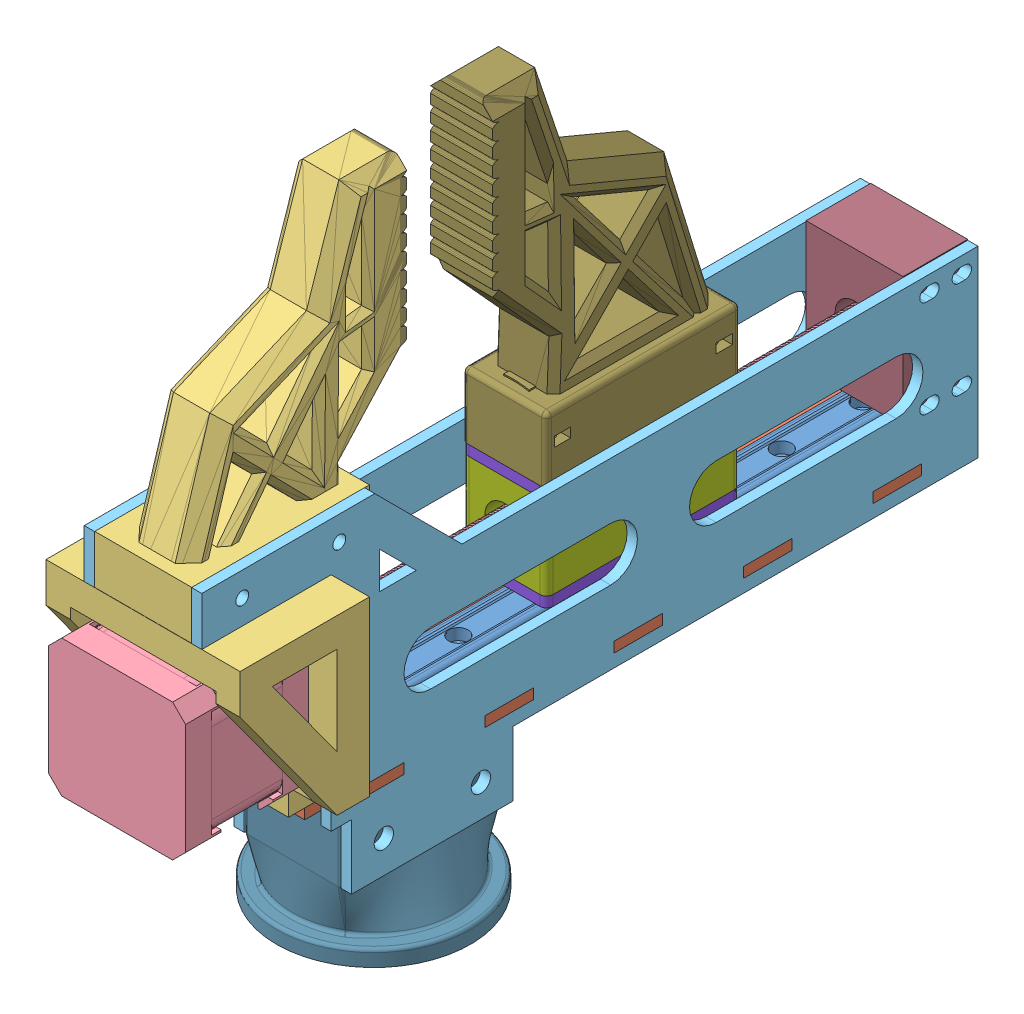
SolidWorks assembly CAD, configuration Default. Lengths in mm.
Overall size (60 201.12 248).
17 component instances, 14 part files, 31 mates.
Components (placement in the parent):
- Em4HMIiUfR_CADModel_0-1: Em4HMIiUfR_CADModel_0 [Default] at origin size (13.08 8.01 200)
- Part1-1: Part1 [Default] at (-24.2561 0 -84.2912) x (1 0 0) z (0 1 0) size (36.35 200 3.17)
- Part4-1: Part4 [Default] at (30 8.03 40) x (-1 0 0) z (0 0 -1) size (60 153.95 71.54)
- Stepper with LeadScrew-1: Stepper with LeadScrew [Default] at (0 29.78 18) x (1 0 0) z (0 1 0) size (42.3 239.5 42.3)
- Part2-1: Part2 [Default] at (18.175 145.03 -15) x (0 0 -1) z (1 0 0) size (240 103.7 3.17)
- 7917N13_HIGH-CYCLE LOW-PROFILE BALL BEARING CARRIAGE-1: 7917N13_HIGH-CYCLE LOW-PROFILE BALL BEARING CARRIAGE [7917N13] at (0.4 7.1 -102.0336) size (27 11 34.4)
- spring mech-1: spring mech [Default] at (6.5573 38.7283 -72.0092) x (0 0 1) z (0 -1 0) size (60 26 32.35)
  - Block1-1: Block1 [Default] at (-59.7244 -6.4427 -4.0467) size (60 26 26)
  - spring plate-1: spring plate [Default] at (-59.7244 -6.4427 -4.0467) x (-1 0 0) z (0 0 -1) size (60 26 3.17)
  - spring plate-2: spring plate [Default] at (0.2756 -6.4427 21.9533) size (60 26 3.17)
  - leadnut-1: leadnut [Default] at (-36.9744 6.5573 8.9533) x (-1 0 0) z (0 -1 0) size (10 24 10.5)
  - 9434K135_MUSIC-WIRE STEEL COMPRESSION SPRINGS-1: 9434K135_MUSIC-WIRE STEEL COMPRESSION SPRINGS [9434K135] at (-41.4744 6.4644 9.0297) x (0 -1 0) z (0 0 1) size (15.72 32.66 15.84)
  - guide block-1: guide block [Default] at (-41.4744 -1.4427 21.9533) x (0 1 0) z (-1 0 0) size (16 26 7)
- pincher-1: pincher [Default] at (-85.0656 -1.6348 38.7958) x (1 0 0) z (0 1 0) size (26 73.24 107.42)
- Part2-2: Part2 [Default] at (-15 145.03 -15) x (0 0 -1) z (1 0 0) size (240 103.7 3.17)
- Part3-1: Part3 [Default] at (-15 9.78 -200) size (30 40 20)
- Circular Wrist Adapter Mount-1: Circular Wrist Adapter Mount [Default] at (0 -42.175 -31.2815) x (0 0 1) z (0 1 0) size (60 60 40)
Mates (geometry in assembly coordinates):
- Coincident1: coincident anti-aligned: plane of Em4HMIiUfR_CADModel_0-1 through (-5.8438 0 -200) normal (0 -1 0); plane of Part1-1 through (-24.2561 0 -84.2912) normal (0 1 0)
- Coincident2: coincident aligned: circle of Em4HMIiUfR_CADModel_0-1; cylinder of Part1-1 through (0 -3.175 -32.5) axis (0 1 0) radius 1.75
- Concentric2: concentric aligned: circle of Em4HMIiUfR_CADModel_0-1; circle of Part1-1
- Concentric3: concentric aligned: circle of Part4-1; circle of Stepper with LeadScrew-1
- Coincident3: coincident anti-aligned: plane of Part4-1 through (30 8.03 10) normal (0 0 1); plane of Stepper with LeadScrew-1 through (0 29.78 10) normal (0 0 -1)
- Parallel1: parallel aligned: plane of Part4-1 through (-30 48.03 0) normal (-1 0 0); plane of Stepper with LeadScrew-1 through (-21.1 44.68 40) normal (-1 0 0)
- Distance1: distance = 5 mm anti-aligned: plane of Part1-1 through (-18.175 -3.175 5) normal (0 0 1); plane of Part4-1 through (30 8.03 0) normal (0 0 -1)
- Parallel2: parallel anti-aligned: plane of Part1-1 through (-24.2561 -3.175 -84.2912) normal (0 -1 0); plane of Part4-1 through (-15 76.53 39.9268) normal (0 1 0)
- Coincident7: coincident aligned: plane of Part1-1 through (-15 -10 17.5) normal (-1 0 0); plane of Part4-1 through (-15 8.03 40) normal (-1 0 0)
- Coincident8: coincident anti-aligned: plane of Part1-1 through (18.175 -10 -7.5) normal (0 0 1); plane of Part2-1 through (15 -3.175 -7.5) normal (0 0 -1)
- Coincident9: coincident anti-aligned: plane of Part1-1 through (15 -10 17.5) normal (1 0 0); plane of Part2-1 through (15 145.03 -15) normal (-1 0 0)
- Coincident10: coincident anti-aligned: plane of Part1-1 through (-24.2561 0 -84.2912) normal (0 1 0); plane of Part2-1 through (15 0 -102.5) normal (0 -1 0)
- Distance2: distance = 13 mm aligned: plane of 7917N13_HIGH-CYCLE LOW-PROFILE BALL BEARING CARRIAGE-1 through (-12 13 -112.3336) normal (0 1 0); plane of Part1-1 through (-24.2561 0 -84.2912) normal (0 1 0)
- Coincident14: coincident anti-aligned: plane of 7917N13_HIGH-CYCLE LOW-PROFILE BALL BEARING CARRIAGE-1 through (-12.69 13.6 -84.8336) normal (0 1 0); plane of spring mech-1/spring plate-2 through (13 13.6 -71.7336) normal (0 -1 0)
- Coincident15: coincident aligned: plane of 7917N13_HIGH-CYCLE LOW-PROFILE BALL BEARING CARRIAGE-1 through (-13 12 -91.7336) normal (-1 0 0); plane of spring mech-1/Block1-1 through (-13 16.775 -129.7336) normal (-1 0 0)
- Distance3: distance = 12.5 mm aligned: plane of 7917N13_HIGH-CYCLE LOW-PROFILE BALL BEARING CARRIAGE-1 through (-5.45 6.9821 -119.2336) normal (0 0 -1); plane of spring mech-1/Block1-1 through (11 16.775 -131.7336) normal (0 0 -1)
- Coincident17: coincident anti-aligned: plane of spring mech-1/spring plate-1 through (13 45.95 -131.7336) normal (0 1 0); plane of pincher-1 through (-85.0656 45.95 38.7958) normal (0 -1 0)
- Coincident18: coincident aligned: plane of spring mech-1/Block1-1 through (11 16.775 -71.7336) normal (0 0 1); plane of pincher-1 through (13 45.95 -71.7336) normal (0 0 1)
- Coincident19: coincident anti-aligned: plane of Part4-1 through (-30 61.53 0) normal (0 1 0); plane of Part2-1 through (15 61.53 40) normal (0 -1 0)
- Distance4: distance = 2 mm anti-aligned: plane of spring mech-1/Block1-1 through (13 16.775 -129.7336) normal (1 0 0); plane of Part2-1 through (15 145.03 -15) normal (-1 0 0)
- Coincident21: coincident aligned: plane of spring mech-1/Block1-1 through (-13 16.775 -129.7336) normal (-1 0 0); plane of pincher-1 through (-13 45.95 -131.7336) normal (-1 0 0)
- Coincident23: coincident anti-aligned: plane of spring mech-1/spring plate-1 through (13 45.95 -131.7336) normal (0 1 0); plane of pincher-1 through (-85.0656 45.95 38.7958) normal (0 -1 0)
- Coincident24: coincident anti-aligned: plane of Part4-1 through (-15 8.03 40) normal (-1 0 0); plane of Part2-2 through (-15 145.03 -15) normal (1 0 0)
- Coincident25: coincident aligned: plane of Part2-1 through (15 49.53 -200) normal (0 0 -1); plane of Part2-2 through (-18.175 49.53 -200) normal (0 0 -1)
- Concentric4: concentric anti-aligned: circle of Part4-1; cylinder of Part3-1 through (0 29.78 -192) axis (0 0 1) radius 6
- Coincident27: coincident aligned: plane of Part2-2 through (-18.175 49.53 -200) normal (0 0 -1); plane of Part3-1 through (-15 9.78 -200) normal (0 0 -1)
- Coincident28: coincident anti-aligned: plane of Part2-2 through (-15 145.03 -15) normal (1 0 0); plane of Circular Wrist Adapter Mount-1 through (-15 -7.175 -56.2815) normal (-1 0 0)
- Coincident33: coincident aligned: line of Part1-1 through (-18.175 0 -182.5) axis (0 0 1); line of Part2-2 through (-18.175 0 -182.5) axis (0 0 1)
- Width1: width anti-aligned: plane of Circular Wrist Adapter Mount-1 through (15 -7.175 -56.2815) normal (1 0 0); plane of Part2-1 through (-15 -7.175 -56.2815) normal (-1 0 0); plane of Circular Wrist Adapter Mount-1 through (15 145.03 -15) normal (-1 0 0); plane of Part2-2 through (-15 145.03 -15) normal (1 0 0)
- Width2: width anti-aligned: plane of Circular Wrist Adapter Mount-1 through (-15 -7.175 -56.2815) normal (0 0 -1); plane of Part2-1 through (-15 -7.175 -6.2815) normal (0 0 1); plane of Circular Wrist Adapter Mount-1 through (15 -7.175 -6.2815) normal (0 0 1); plane of Part2-1 through (15 -7.175 -56.2815) normal (0 0 -1)
- Coincident34: coincident aligned: line of Part2-1 through (15 -27.175 -6.2815) axis (0 0 -1); line of Circular Wrist Adapter Mount-1 through (15 -27.175 -7.2831) axis (0 0 -1)
